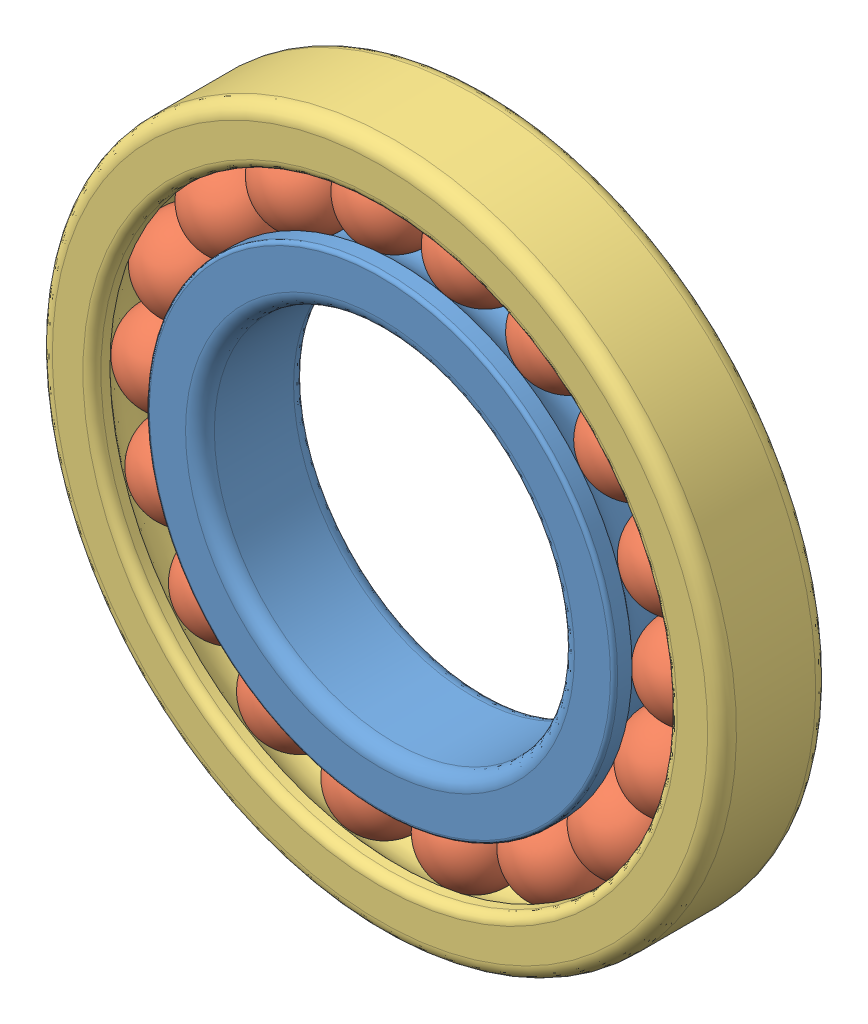
SolidWorks assembly 轴承, configuration 默认. Lengths in mm.
Overall size (38 38 6).
21 component instances, 4 part files, 3 mates.
Components (placement in the parent):
- 零件1^轴承-1: 零件1^轴承 [默认] at origin (virtual)
- 轴承内环-1: 轴承内环 [默认] at (-32.2968 1.2734 5.1505) size (26 26 6)
- 钢珠-1: 钢珠 [默认] at (-43.5507 -7.7988 8.1112) size (5 5 5)
- 钢珠-2: 钢珠 [默认] at (-45.9749 -3.4026 8.1112) x (0.939693 -0.34202 0) z (0 0 1) size (5 5 5)
- 钢珠-3: 钢珠 [默认] at (-46.7492 1.5576 8.1112) x (0.766044 -0.642788 0) z (0 0 1) size (5 5 5)
- 钢珠-4: 钢珠 [默认] at (-45.7805 6.4834 8.1112) x (0.5 -0.866025 0) z (0 0 1) size (5 5 5)
- 钢珠-5: 钢珠 [默认] at (-43.1854 10.7809 8.1112) x (0.173648 -0.984808 0) z (0 0 1) size (5 5 5)
- 钢珠-6: 钢珠 [默认] at (-39.2769 13.9316 8.1112) x (-0.173648 -0.984808 0) z (0 0 1) size (5 5 5)
- 钢珠-7: 钢珠 [默认] at (-34.5266 15.5556 8.1112) x (-0.5 -0.866025 0) z (0 0 1) size (5 5 5)
- 钢珠-8: 钢珠 [默认] at (-29.5073 15.4569 8.1112) x (-0.766044 -0.642788 0) z (0 0 1) size (5 5 5)
- 钢珠-9: 钢珠 [默认] at (-24.8245 13.6474 8.1112) x (-0.939693 -0.34202 0) z (0 0 1) size (5 5 5)
- 钢珠-10: 钢珠 [默认] at (-21.043 10.3455 8.1112) x (-1 0 0) z (0 0 1) size (5 5 5)
- 钢珠-11: 钢珠 [默认] at (-18.6188 5.9493 8.1112) x (-0.939693 0.34202 0) z (0 0 1) size (5 5 5)
- 钢珠-12: 钢珠 [默认] at (-17.8444 0.9892 8.1112) x (-0.766044 0.642788 0) z (0 0 1) size (5 5 5)
- 钢珠-13: 钢珠 [默认] at (-18.8132 -3.9367 8.1112) x (-0.5 0.866025 0) z (0 0 1) size (5 5 5)
- 钢珠-14: 钢珠 [默认] at (-21.4083 -8.2342 8.1112) x (-0.173648 0.984808 0) z (0 0 1) size (5 5 5)
- 钢珠-15: 钢珠 [默认] at (-25.3168 -11.3849 8.1112) x (0.173648 0.984808 0) z (0 0 1) size (5 5 5)
- 钢珠-16: 钢珠 [默认] at (-30.0671 -13.0088 8.1112) x (0.5 0.866025 0) z (0 0 1) size (5 5 5)
- 钢珠-17: 钢珠 [默认] at (-35.0863 -12.9101 8.1112) x (0.766044 0.642788 0) z (0 0 1) size (5 5 5)
- 钢珠-18: 钢珠 [默认] at (-39.7692 -11.1007 8.1112) x (0.939693 0.34202 0) z (0 0 1) size (5 5 5)
- 轴承外环-1: 轴承外环 [默认] at (-32.2968 1.2734 11.1505) x (1 0 0) z (0 1 0) size (38 6 38)
Mates (geometry in assembly coordinates):
- 锁定1: lock: unknown of ?; unknown of ?
- 同心1: concentric anti-aligned: cylinder of 轴承内环-1 through (-32.2968 1.2734 11.1505) axis (0 0 -1) radius 10; cylinder of 轴承外环-1 through (-32.2968 1.2734 5.1505) axis (0 0 1) radius 19
- 重合1: coincident aligned: plane of 轴承内环-1 through (-32.2968 1.2734 5.1505) normal (0 0 -1); plane of 轴承外环-1 through (-32.2968 1.2734 5.1505) normal (0 0 -1)
